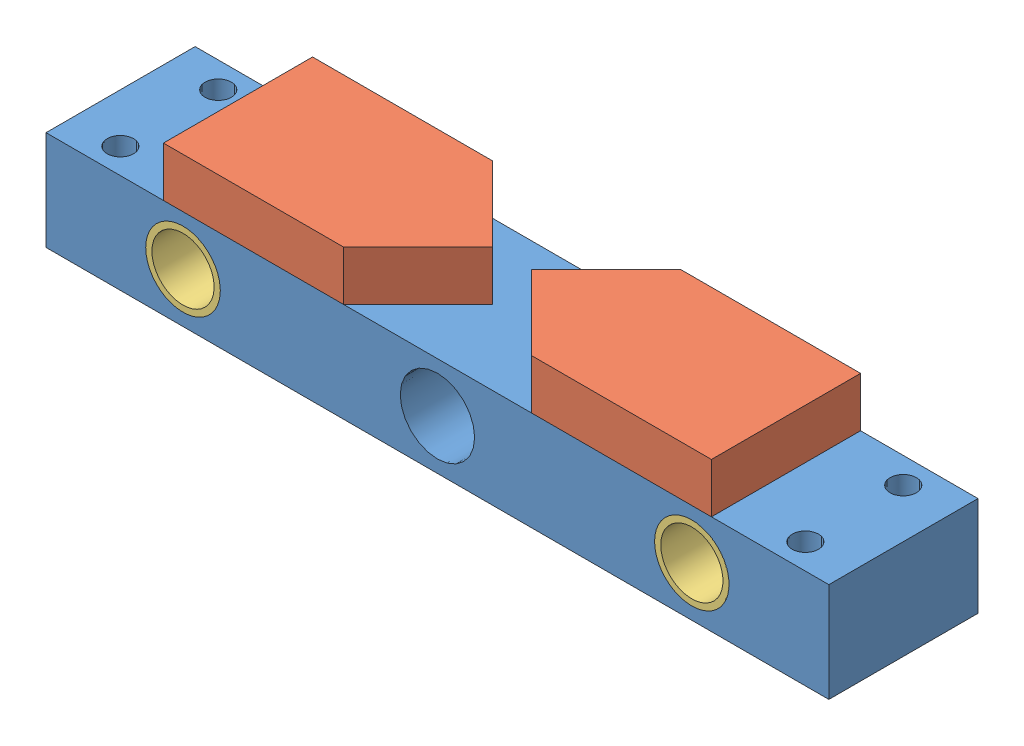
SolidWorks assembly 80model, configuration Default. Lengths in mm.
Overall size (400 76.2 76.2).
5 component instances, 3 part files, 10 mates.
Components (placement in the parent):
- FixedBlock-1: FixedBlock [Default] at (-191.6129 -46.7792 48.199) size (400 50.8 76.2)
- Raiser-1: Raiser [Default] at (-131.6129 4.0208 48.199) size (130 25.4 76.2)
- Raiser-2: Raiser [Default] at (148.3871 4.0208 -28.001) x (-1 0 0) z (0 0 -1) size (130 25.4 76.2)
- 67model-1: 67model [Default] at (-121.6129 -21.3792 -28.001) size (38.1 38.1 76.2)
- 67model-2: 67model [Default] at (138.3871 -21.3792 -28.001) size (38.1 38.1 76.2)
Mates (geometry in assembly coordinates):
- Coincident1: coincident anti-aligned: plane of FixedBlock-1 through (-191.6129 4.0208 -28.001) normal (0 1 0); plane of Raiser-1 through (-183.961 4.0208 10.099) normal (0 -1 0)
- Coincident2: coincident anti-aligned: plane of FixedBlock-1 through (-191.6129 4.0208 -28.001) normal (0 1 0); plane of Raiser-2 through (200.7351 4.0208 10.099) normal (0 -1 0)
- Distance1: distance = 60 mm aligned: plane of Raiser-2 through (148.3871 29.4208 10.099) normal (1 0 0); plane of FixedBlock-1 through (208.3871 4.0208 48.199) normal (1 0 0)
- Coincident4: coincident aligned: plane of FixedBlock-1 through (-191.6129 4.0208 48.199) normal (0 0 1); plane of Raiser-2 through (200.7351 29.4208 48.199) normal (0 0 1)
- Coincident5: coincident aligned: plane of FixedBlock-1 through (-191.6129 4.0208 48.199) normal (0 0 1); plane of Raiser-1 through (-183.961 29.4208 48.199) normal (0 0 1)
- Distance2: distance = 60 mm aligned: plane of Raiser-1 through (-131.6129 29.4208 10.099) normal (-1 0 0); plane of FixedBlock-1 through (-191.6129 4.0208 48.199) normal (-1 0 0)
- Concentric1: concentric anti-aligned: cylinder of FixedBlock-1 through (-121.6129 -21.3792 -28.001) axis (0 0 1) radius 19; cylinder of 67model-1 through (-121.6129 -21.3792 48.199) axis (0 0 -1) radius 19.05
- Concentric2: concentric: cylinder of FixedBlock-1 through (138.3871 -21.3792 -28.001) axis (0 0 1) radius 19; cylinder of 67model-2 through (138.3871 -21.3792 48.199) axis (0 0 -1) radius 19.05
- Coincident7: coincident aligned: plane of FixedBlock-1 through (-191.6129 4.0208 48.199) normal (0 0 1); plane of 67model-1 through (-121.6129 -21.3792 48.199) normal (0 0 1)
- Coincident9: coincident aligned: plane of FixedBlock-1 through (-191.6129 4.0208 48.199) normal (0 0 1); circle of 67model-2
